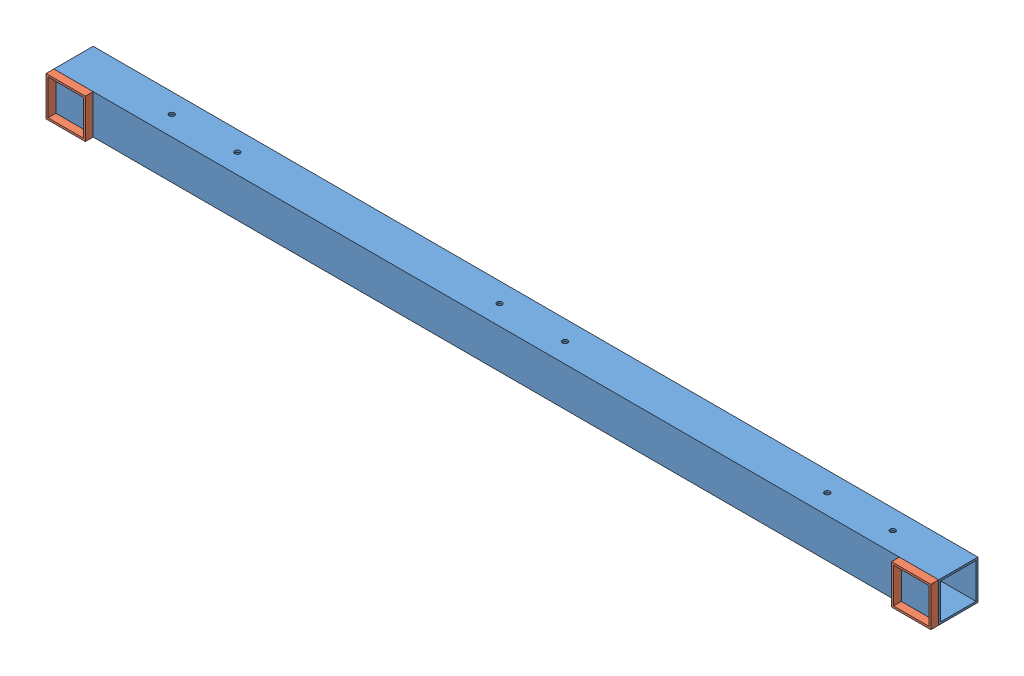
SolidWorks assembly Longeron675MobileAvecRehausseur, configuration Défaut. Lengths in mm.
Overall size (675 30 36).
3 component instances, 2 part files, 2 mates.
Components (placement in the parent):
- LongeronMobile675mm-1: LongeronMobile675mm [Défaut] at (-360.8062 12.9587 15) size (675 30 30)
- rehausseur 6mm-1: rehausseur 6mm [Défaut] at (-360.8062 -17.0413 21) x (1 0 0) z (0 1 0) size (30 6 30)
- rehausseur 6mm-2: rehausseur 6mm [Défaut] at (284.1938 -17.0413 21) x (1 0 0) z (0 1 0) size (30 6 30)
Mates (geometry in assembly coordinates):
- Coïncidente1: coincident anti-aligned: plane of LongeronMobile675mm-1 through (314.1938 12.9587 15) normal (0 0 1); plane of rehausseur 6mm-1 through (-360.8062 -17.0413 15) normal (0 0 -1)
- Coïncidente2: coincident: point of LongeronMobile675mm-1; point of rehausseur 6mm-1
